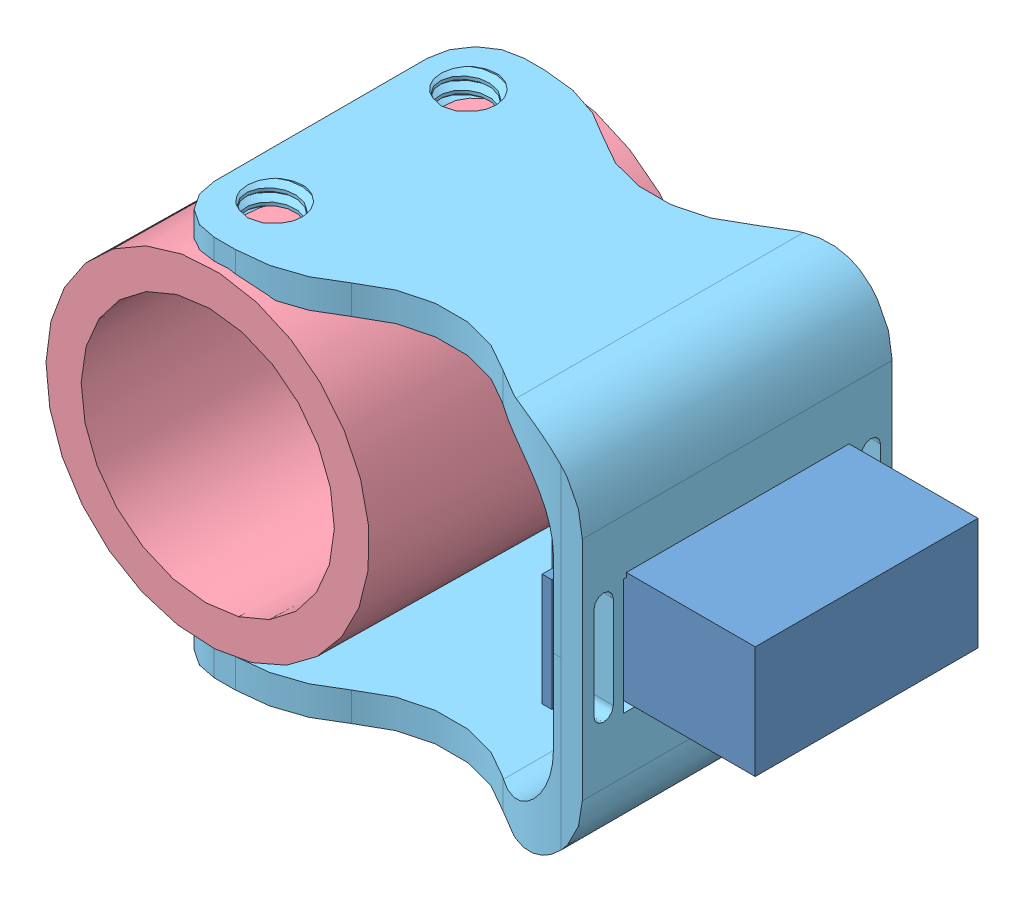
SolidWorks assembly Adjustable Valve, configuration Default. Lengths in mm.
Overall size (67.53 40.24 37.1).
7 component instances, 7 part files, 11 mates.
Components (placement in the parent):
- Bottom_Plate-1: Bottom_Plate [Default] at origin size (49.7 35.12 32) (hidden)
- Servo Motor-1: Servo Motor [Default] at (1 3.404 0) x (0 0 -1) z (1 0 0) size (32 11.6 24.7)
- Servo Horn^Adjustable Valve-1: Servo Horn^Adjustable Valve [Default] at (-12.0988 3.3406 -11.536) x (0 -0.999577 0.029097) z (-1 0 0) size (17.5 6 8) (virtual)
- Valve-1: Valve [Default] at (-39.2377 9.0969 -4.0038) x (0 -0.997448 -0.071398) z (0 0.071398 -0.997448) size (27.6 26 26.4)
- PVC_1in_Sch40-1: PVC_1in_Sch40 [Default] at (-39.3319 9.3916 7.1986) x (0 0.999891 -0.014772) z (-1 0 0) size (33.4 35 33.4)
- Mount_Bracket-1: Mount_Bracket [Default] at (-34.8049 8.5581 16.0553) x (0 1 0) z (-1 0 0) size (40.24 32 43)
- Rod Mount-2: Rod Mount [Default] at (-20.5 9.204 -5.5) x (0 -0.029097 -0.999577) z (0 -0.999577 0.029097) size (6 3 17.5)
Mates (geometry in assembly coordinates):
- Concentric1: concentric: cylinder of Bottom_Plate-1 through (-11 10.004 13.8) axis (1 0 0) radius 1; cylinder of Servo Motor-1 through (-1 10.004 13.8) axis (-1 0 0) radius 1
- Concentric5: concentric: cylinder of Bottom_Plate-1 through (-11 10.004 -13.8) axis (1 0 0) radius 1; cylinder of Servo Motor-1 through (-1 10.004 -13.8) axis (-1 0 0) radius 1
- Concentric10: concentric aligned: cylinder of Servo Motor-1 through (-13.2 9.204 -5.5) axis (1 0 0) radius 0.6; cylinder of Servo Horn^Ventilator Valve-1 through (-14.5 9.204 -5.5) axis (1 0 0) radius 2
- Coincident7: coincident anti-aligned: plane of Servo Motor-1 through (-9.5 15.004 11.5) normal (-1 0 0); plane of Servo Horn^Ventilator Valve-1 through (-9.5 9.204 -5.5) normal (1 0 0)
- Concentric11: concentric anti-aligned: cylinder of Servo Horn^Ventilator Valve-1 through (-14.5 9.204 -5.5) axis (1 0 0) radius 2; cylinder of Valve-1 through (-26.0322 9.204 -5.5) axis (-1 0 0) radius 1.5
- Concentric19: concentric aligned: cylinder of Servo Horn^Ventilator Valve-1 through (-14.5 9.204 -5.5) axis (1 0 0) radius 2; cylinder of Rod Mount-1 through (-20.5 9.204 -5.5) axis (1 0 0) radius 1.5
- Concentric22: concentric anti-aligned: cylinder of Servo Horn^Ventilator Valve-1 through (-7.5 22.1985 -5.8783) axis (-1 0 0) radius 0.5; cylinder of Rod Mount-1 through (-20.5 22.1985 -5.8783) axis (1 0 0) radius 0.5
- Coincident20: coincident anti-aligned: plane of Servo Horn^Ventilator Valve-1 through (-17.5 3.3406 -11.536) normal (-1 0 0); plane of Rod Mount-1 through (-17.5 21.9486 -5.871) normal (1 0 0)
- Coincident21: coincident anti-aligned: plane of Servo Horn^Adjustable Valve-1 through (-17.5 3.3406 -11.536) normal (-1 0 0); plane of Rod Mount-2 through (-17.5 14.9643 -16.8746) normal (1 0 0)
- Concentric23: concentric anti-aligned: circle of Servo Horn^Adjustable Valve-1; cylinder of Rod Mount-2 through (-17.5 9.204 -5.5) axis (-1 0 0) radius 1.5
- Concentric24: concentric anti-aligned: circle of Servo Horn^Adjustable Valve-1; circle of Rod Mount-2
